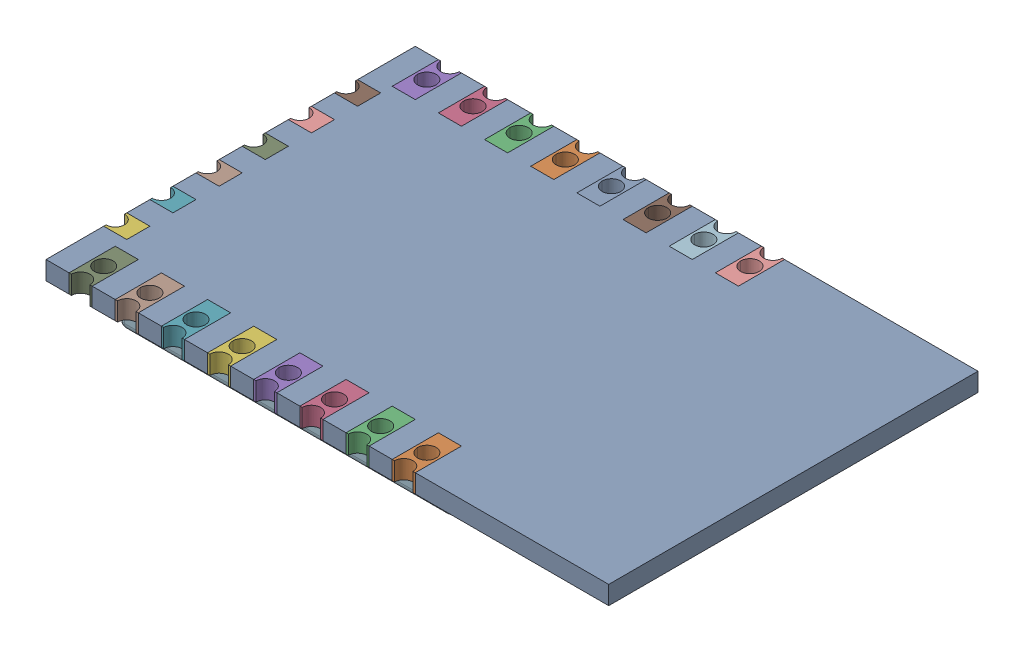
SolidWorks assembly 0411-2, configuration ﾃﾞﾌｫﾙﾄ. Lengths in mm.
Overall size (24.38 3.05 16).
26 component instances, 6 part files, 0 mates.
Components (placement in the parent):
- User_Library-ESP8266-12E_PCB1-1: User_Library-ESP8266-12E_PCB1 [ﾃﾞﾌｫﾙﾄ] x (-1 0 0) z (0 0 1) size (24.38 0.8 16)
- User_Library-ESP8266-12E_Pin1-1: User_Library-ESP8266-12E_Pin1 [ﾃﾞﾌｫﾙﾄ] at (3.31 0 8) x (-1 0 0) z (0 -1 0) size (1 2 0.8)
- User_Library-ESP8266-12E_Pin1-2: User_Library-ESP8266-12E_Pin1 [ﾃﾞﾌｫﾙﾄ] at (1.31 0 8) x (-1 0 0) z (0 -1 0) size (1 2 0.8)
- User_Library-ESP8266-12E_Pin1-3: User_Library-ESP8266-12E_Pin1 [ﾃﾞﾌｫﾙﾄ] at (-0.69 0 8) x (-1 0 0) z (0 -1 0) size (1 2 0.8)
- User_Library-ESP8266-12E_Pin1-4: User_Library-ESP8266-12E_Pin1 [ﾃﾞﾌｫﾙﾄ] at (-2.69 0 8) x (-1 0 0) z (0 -1 0) size (1 2 0.8)
- User_Library-ESP8266-12E_Pin1-5: User_Library-ESP8266-12E_Pin1 [ﾃﾞﾌｫﾙﾄ] at (-4.69 0 8) x (-1 0 0) z (0 -1 0) size (1 2 0.8)
- User_Library-ESP8266-12E_Pin1-6: User_Library-ESP8266-12E_Pin1 [ﾃﾞﾌｫﾙﾄ] at (-6.69 0 8) x (-1 0 0) z (0 -1 0) size (1 2 0.8)
- User_Library-ESP8266-12E_Pin1-7: User_Library-ESP8266-12E_Pin1 [ﾃﾞﾌｫﾙﾄ] at (-8.69 0 8) x (-1 0 0) z (0 -1 0) size (1 2 0.8)
- User_Library-ESP8266-12E_Pin1-8: User_Library-ESP8266-12E_Pin1 [ﾃﾞﾌｫﾙﾄ] at (-10.69 0 8) x (-1 0 0) z (0 -1 0) size (1 2 0.8)
- User_Library-ESP8266-12E_Pin1-9: User_Library-ESP8266-12E_Pin1 [ﾃﾞﾌｫﾙﾄ] at (3.31 0 -8) x (1 0 0) z (0 -1 0) size (1 2 0.8)
- User_Library-ESP8266-12E_Pin1-10: User_Library-ESP8266-12E_Pin1 [ﾃﾞﾌｫﾙﾄ] at (-0.69 0 -8) x (1 0 0) z (0 -1 0) size (1 2 0.8)
- User_Library-ESP8266-12E_Pin1-11: User_Library-ESP8266-12E_Pin1 [ﾃﾞﾌｫﾙﾄ] at (1.31 0 -8) x (1 0 0) z (0 -1 0) size (1 2 0.8)
- User_Library-ESP8266-12E_Pin1-12: User_Library-ESP8266-12E_Pin1 [ﾃﾞﾌｫﾙﾄ] at (-2.69 0 -8) x (1 0 0) z (0 -1 0) size (1 2 0.8)
- User_Library-ESP8266-12E_Pin1-13: User_Library-ESP8266-12E_Pin1 [ﾃﾞﾌｫﾙﾄ] at (-4.69 0 -8) x (1 0 0) z (0 -1 0) size (1 2 0.8)
- User_Library-ESP8266-12E_Pin1-14: User_Library-ESP8266-12E_Pin1 [ﾃﾞﾌｫﾙﾄ] at (-6.69 0 -8) x (1 0 0) z (0 -1 0) size (1 2 0.8)
- User_Library-ESP8266-12E_Pin1-15: User_Library-ESP8266-12E_Pin1 [ﾃﾞﾌｫﾙﾄ] at (-8.69 0 -8) x (1 0 0) z (0 -1 0) size (1 2 0.8)
- User_Library-ESP8266-12E_Pin1-16: User_Library-ESP8266-12E_Pin1 [ﾃﾞﾌｫﾙﾄ] at (-10.69 0 -8) x (1 0 0) z (0 -1 0) size (1 2 0.8)
- User_Library-ESP8266-12E_Pin2-1: User_Library-ESP8266-12E_Pin2 [ﾃﾞﾌｫﾙﾄ] at (-12.19 0 5) x (0 0 1) z (0 1 0) size (1 1 0.8)
- User_Library-ESP8266-12E_Pin2-2: User_Library-ESP8266-12E_Pin2 [ﾃﾞﾌｫﾙﾄ] at (-12.19 0 3) x (0 0 -1) z (0 -1 0) size (1 1 0.8)
- User_Library-ESP8266-12E_Pin2-3: User_Library-ESP8266-12E_Pin2 [ﾃﾞﾌｫﾙﾄ] at (-12.19 0 1) x (0 0 1) z (0 1 0) size (1 1 0.8)
- User_Library-ESP8266-12E_Pin2-4: User_Library-ESP8266-12E_Pin2 [ﾃﾞﾌｫﾙﾄ] at (-12.19 0 -1) x (0 0 1) z (0 1 0) size (1 1 0.8)
- User_Library-ESP8266-12E_Pin2-5: User_Library-ESP8266-12E_Pin2 [ﾃﾞﾌｫﾙﾄ] at (-12.19 0 -3) x (0 0 1) z (0 1 0) size (1 1 0.8)
- User_Library-ESP8266-12E_Pin2-6: User_Library-ESP8266-12E_Pin2 [ﾃﾞﾌｫﾙﾄ] at (-12.19 0 -5) x (0 0 1) z (0 1 0) size (1 1 0.8)
- User_Library-ESP8266-12E_Lid-1: User_Library-ESP8266-12E_Lid [ﾃﾞﾌｫﾙﾄ] at (-3.84 -1.5 0.25) x (0 0 -1) z (0 -1 0) size (11.5 14.5 2.25)
- User_Library-ESP8266-12E_Antenne-1: User_Library-ESP8266-12E_Antenne [ﾃﾞﾌｫﾙﾄ] at (4.99 -0.425 6) x (0 0 -1) z (0 -1 0) size (12.3 7 0.05)
- User_Library-ESP8266-12E_Surface_Mount_Chip_LED_3.2x1.6mm-1: User_Library-ESP8266-12E_Surface_Mount_Chip_LED_3.2x1.6mm [ﾃﾞﾌｫﾙﾄ] at (6.19 -0.41 -7.5) x (0 0 1) z (0 -1 0) size (3.2 1.6 1.13)
